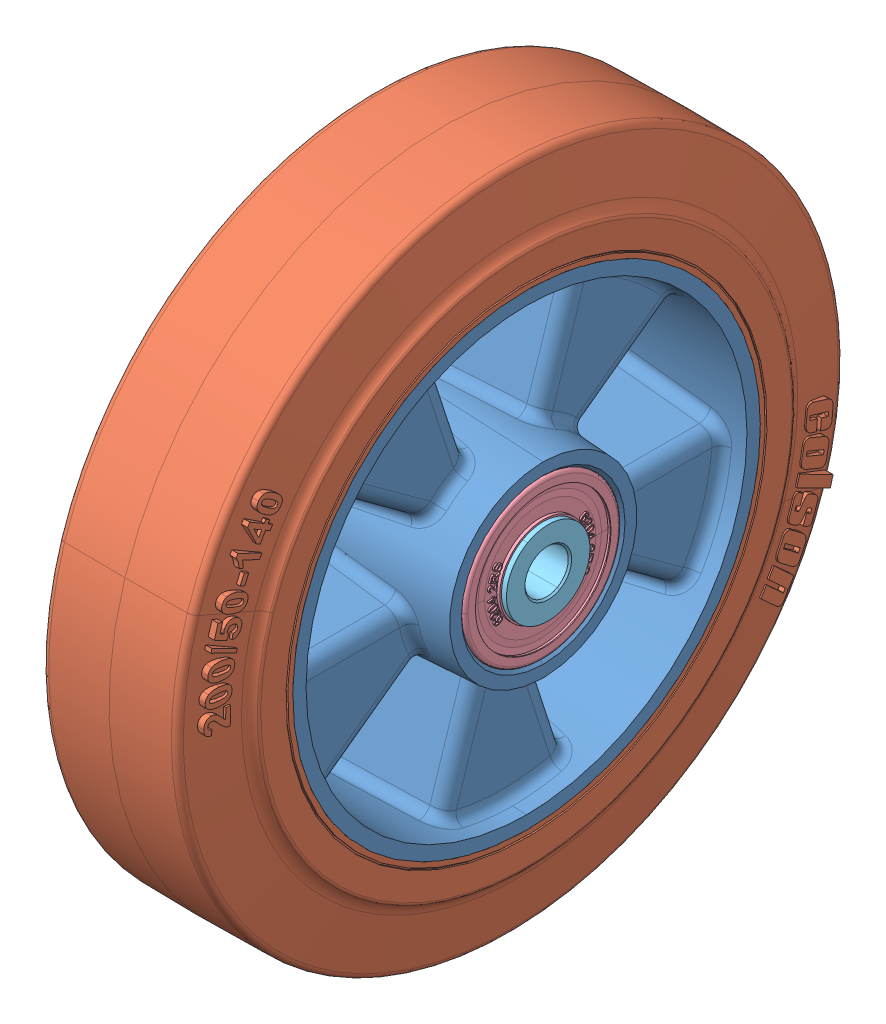
SolidWorks assembly WHAB200, configuration Default. Lengths in mm.
Overall size (63 251.54 251.54).
7 component instances, 5 part files, 0 mates.
Components (placement in the parent):
- Piasta AB140_Domy_lna-1: Piasta AB140_Domy_lna [Default] at (79.5654 80.9649 88.8329) size (60 140.87 140.87)
- GUMA AB200-1: GUMA AB200 [Default] at (79.5654 80.9649 88.8329) x (0 0.305535 0.952181) z (1 0 0) size (200 200 50)
- Bushing 25x21x32_B.25x21x32^WHAB200-1: Bushing 25x21x32_B.25x21x32^WHAB200 [Default] at (95.5654 80.9649 88.8329) x (0 0 1) z (-1 0 0) size (25 25 32) (virtual)
- 6204-2RS-1: 6204-2RS [Default] at (95.5654 80.9649 88.8329) size (14 47 47)
- 6204-2RS-2: 6204-2RS [Default] at (49.5654 80.9649 88.8329) size (14 47 47)
- BUS25x20x13x21_B.25x29x13x21^WHAB200-1: BUS25x20x13x21_B.25x29x13x21^WHAB200 [Default] at (49.5654 80.9649 88.8329) x (0 0.924225 0.381849) z (-1 0 0) size (25 25 21) (virtual)
- BUS25x20x13x21_B.25x29x13x21^WHAB200-2: BUS25x20x13x21_B.25x29x13x21^WHAB200 [Default] at (109.5654 80.9649 88.8329) x (0 0.869905 0.49322) z (1 0 0) size (25 25 21) (virtual)
